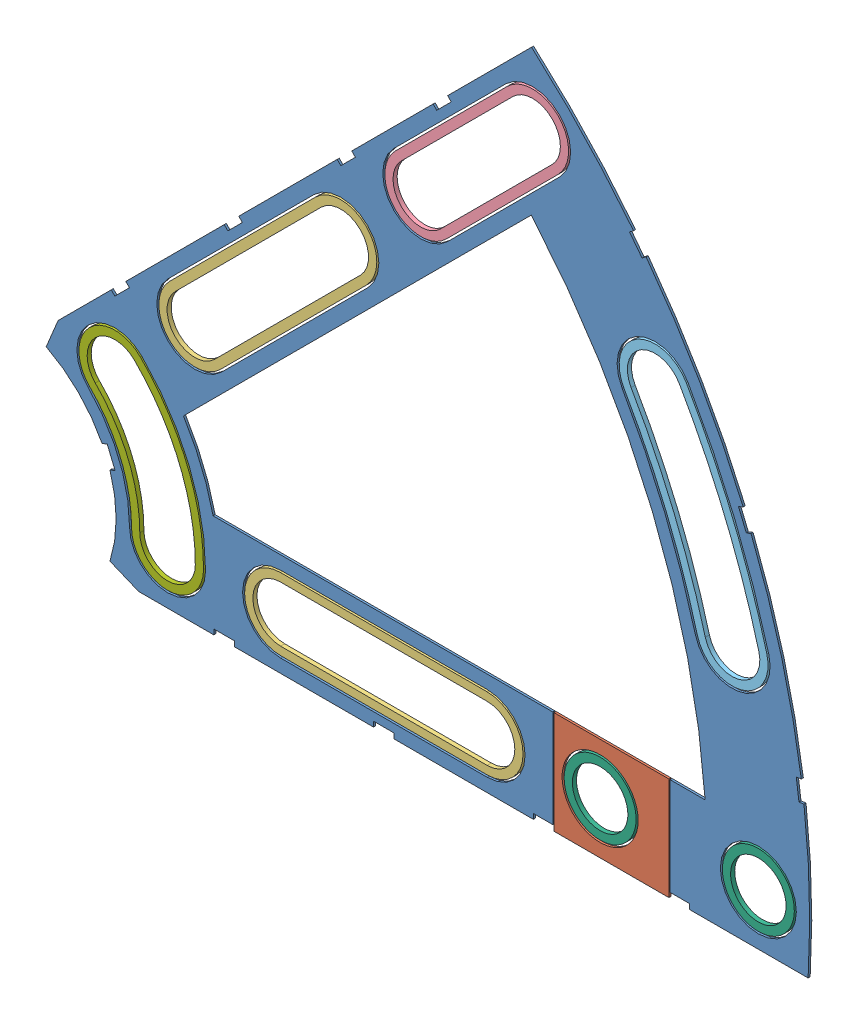
SolidWorks assembly Clover_9_Insul+Pass, configuration Default. Lengths in mm.
Overall size (96.77 82.54 0.51).
9 component instances, 7 part files, 22 mates.
Components (placement in the parent):
- Clover_9_Insul-1: Clover_9_Insul [Default] at (-1.887 41.9506 96.9797) size (94.37 82.54 0.25)
- Clover_9_Pass-1: Clover_9_Pass [Default] at (-1.887 41.9506 96.9797) size (14.22 12.7 0.25)
- Clover_Long_Washer-1: Clover_Long_Washer [Default] at (32.7319 76.5695 97.2337) x (0.707107 0.707107 0) z (-0.707107 0.707107 0) size (34.42 0.51 8.89)
- Clover_Long_Washer-2: Clover_Long_Washer [Default] at (47.0715 41.9506 97.2337) x (1 0 0) z (0 1 0) size (34.42 0.51 8.89)
- Clover_Med_Washer-1: Clover_Med_Washer [Default] at (58.5501 102.3877 97.2337) x (0.707107 0.707107 0) z (-0.707107 0.707107 0) size (28.45 0.51 8.89)
- Clover_Outside_Washer-1: Clover_Outside_Washer [Default] at (-1.887 41.9506 97.2337) x (0.866025 0.5 0) z (-0.5 0.866025 0) size (12.14 0.51 33.54)
- Round_Washer-1: Round_Washer [Default] at (73.805 41.9506 97.2337) x (1 0 0) z (0 1 0) size (8.89 0.51 8.89)
- Round_Washer-2: Round_Washer [Default] at (93.363 41.9506 97.2337) x (1 0 0) z (0 1 0) size (8.89 0.51 8.89)
- Curve_Inner_Washer-1: Curve_Inner_Washer [Default] at (-1.887 41.9506 97.2337) x (0.707107 0.707107 0) z (-0.707107 0.707107 0) size (15.4 0.51 24.61)
Mates (geometry in assembly coordinates):
- Coincident1: coincident: plane of Clover_9_Insul-1 through (-1.887 41.9506 97.2337) normal (0 0 1); plane of Clover_9_Pass-1 through (-1.887 41.9506 97.2337) normal (0 0 1)
- Coincident2: coincident: plane of Clover_9_Insul-1 through (86.7859 48.3006 97.2337) normal (0 1 0); plane of Clover_9_Pass-1 through (86.7859 48.3006 97.2337) normal (0 1 0)
- Distance1: distance = 2.54 mm: plane of Clover_9_Insul-1 through (65.55 35.6006 96.9797) normal (1 0 0); plane of Clover_9_Pass-1 through (68.09 35.6006 96.9797) normal (-1 0 0)
- Concentric1: concentric: circle of Clover_9_Pass-1; circle of Round_Washer-1
- Coincident3: coincident: plane of Clover_9_Pass-1 through (-1.887 41.9506 97.2337) normal (0 0 1); plane of Round_Washer-1 through (73.805 41.9506 97.2337) normal (0 0 1)
- Concentric2: concentric: circle of Clover_9_Insul-1; circle of Round_Washer-2
- Coincident4: coincident: plane of Clover_9_Insul-1 through (-1.887 41.9506 97.2337) normal (0 0 1); plane of Round_Washer-2 through (93.363 41.9506 97.2337) normal (0 0 1)
- Concentric3: concentric: circle of Clover_9_Insul-1; circle of Clover_Outside_Washer-1
- Concentric4: concentric: circle of Clover_9_Insul-1; circle of Clover_Outside_Washer-1
- Coincident5: coincident: plane of Clover_9_Insul-1 through (-1.887 41.9506 97.2337) normal (0 0 1); plane of Clover_Outside_Washer-1 through (39.3575 65.7631 97.2337) normal (0 0 1)
- Concentric5: concentric: circle of Clover_9_Insul-1; circle of Clover_Med_Washer-1
- Concentric6: concentric: circle of Clover_9_Insul-1; circle of Clover_Med_Washer-1
- Coincident6: coincident: plane of Clover_9_Insul-1 through (-1.887 41.9506 97.2337) normal (0 0 1); plane of Clover_Med_Washer-1 through (51.6353 95.4729 97.2337) normal (0 0 1)
- Concentric7: concentric: circle of Clover_9_Insul-1; circle of Clover_Long_Washer-1
- Concentric8: concentric: circle of Clover_9_Insul-1; circle of Clover_Long_Washer-1
- Coincident7: coincident: plane of Clover_9_Insul-1 through (-1.887 41.9506 97.2337) normal (0 0 1); plane of Clover_Long_Washer-1 through (23.7067 67.5443 97.2337) normal (0 0 1)
- Concentric9: concentric: circle of Clover_9_Insul-1; circle of Curve_Inner_Washer-1
- Concentric10: concentric: circle of Clover_9_Insul-1; circle of Curve_Inner_Washer-1
- Coincident8: coincident: plane of Clover_9_Insul-1 through (-1.887 41.9506 97.2337) normal (0 0 1); plane of Curve_Inner_Washer-1 through (5.9707 49.8083 97.2337) normal (0 0 1)
- Concentric11: concentric: circle of Clover_9_Insul-1; circle of Clover_Long_Washer-2
- Concentric12: concentric: circle of Clover_9_Insul-1; circle of Clover_Long_Washer-2
- Coincident9: coincident: plane of Clover_9_Insul-1 through (-1.887 41.9506 97.2337) normal (0 0 1); plane of Clover_Long_Washer-2 through (34.308 41.9506 97.2337) normal (0 0 1)
